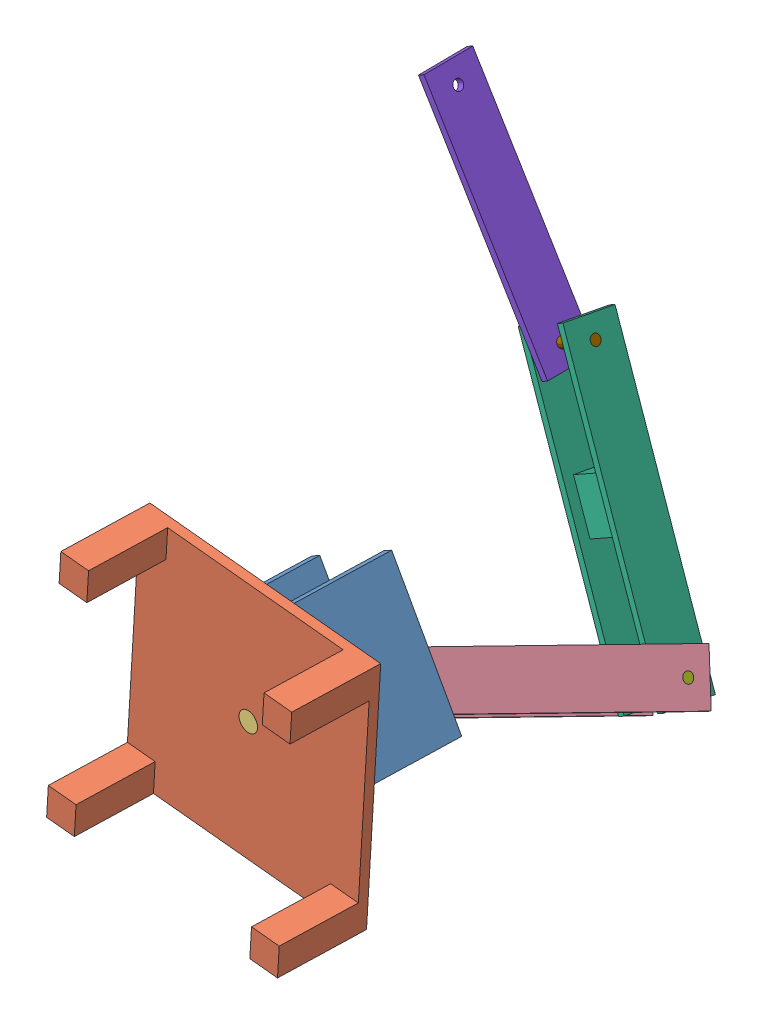
SolidWorks assembly robotgarabo, configuration Predeterminado. Lengths in mm.
Overall size (318.47 465.2 504.02).
10 component instances, 9 part files, 0 mates.
Components (placement in the parent):
- robotgarabo.IGS-1: robotgarabo.IGS [Predeterminado] at origin size (318.47 465.2 504.02)
  - base del brazo.IGS-1: base del brazo.IGS [Predeterminado] at (49.3679 243.6958 211.5896) x (0.50045 -0.86567 0.012876) z (-0.033284 -0.004376 0.999436) size (150.01 100.01 110.01)
  - basedelabasegarabo.IGS-1: basedelabasegarabo.IGS [Predeterminado] at (170.1761 200.4862 255.4462) x (-0.997269 0.066115 -0.032922) z (0.033284 0.004376 -0.999436) size (250.01 250.01 90.01)
  - Perno 4.IGS-1: Perno 4.IGS [Predeterminado] at (53.7592 333.4758 252.1515) x (0.998897 -0.033284 0.03312) z (0.03312 0.999436 0.005479) size (20.01 40.01 20.01)
  - eslabon1robotgarabo.IGS-1: eslabon1robotgarabo.IGS [Predeterminado] at (170.2818 220.382 -108.8665) x (-0.447959 0.799002 -0.40116) z (0.865126 0.500596 0.031002) size (50.01 350.01 80.01)
  - Perno 5.IGS-1: Perno 5.IGS [Predeterminado] at (12.8327 308.7523 180.6408) x (-0.149232 0.315929 -0.936973) z (0.865126 0.500596 0.031002) size (10.01 10.01 100.01)
  - Eslabon 2.IGS-1: Eslabon 2.IGS [Predeterminado] at (147.9869 259.8135 -123.4252) x (-0.097994 0.108083 0.9893) z (-0.865126 -0.500596 -0.031002) size (50.01 300.01 56.01)
  - Prtno 2.IGS-1: Prtno 2.IGS [Predeterminado] at (160.6269 250.5246 -100.3688) x (0.006304 0.050955 -0.998681) z (-0.501516 0.86418 0.040927) size (10.01 80.01 10.01)
  - Eslabon 3.IGS-1: Eslabon 3.IGS [Predeterminado] at (0.8494 432.7231 -164.2417) x (-0.019242 -0.028641 0.999405) z (-0.865126 -0.500596 -0.031002) size (50.01 250.01 7.01)
  - Perno 3.IGS-1: Perno 3.IGS [Predeterminado] at (26.6799 470.3363 -137.6516) x (-0.498867 0.865234 -0.050014) z (-0.051861 0.027802 0.998267) size (10.01 56.01 10.01)
